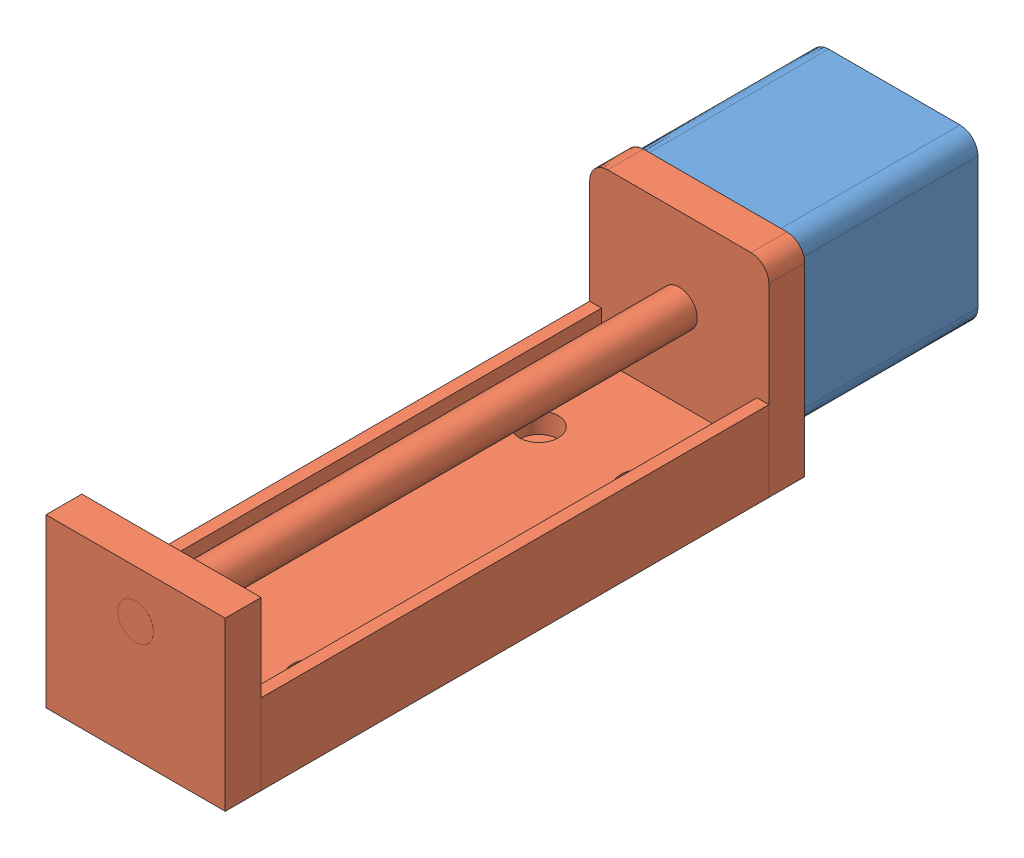
SolidWorks assembly 50mm Stroke Linear Axis, configuration Default. Lengths in mm.
Overall size (30 34 127).
2 component instances, 2 part files, 6 mates.
Components (placement in the parent):
- Nema 11-1: Nema 11 [Default] at origin size (28 29.5 30)
- Gantry-1: Gantry [Stroke 50mm] at origin size (30 34 97)
Mates (geometry in assembly coordinates):
- Coincident1: coincident aligned: plane of Nema 11-1 through (0 0 0) normal (0 0 1)
- Coincident2: coincident aligned: plane of Nema 11-1 through (0 0 0) normal (0 1 0)
- Coincident3: coincident aligned: plane of Nema 11-1 through (0 0 0) normal (1 0 0)
- Coincident4: coincident aligned: plane of Gantry-1 through (0 0 0) normal (0 0 1)
- Coincident5: coincident aligned: plane of Gantry-1 through (0 0 0) normal (0 1 0)
- Coincident6: coincident aligned: plane of Gantry-1 through (0 0 0) normal (1 0 0)
